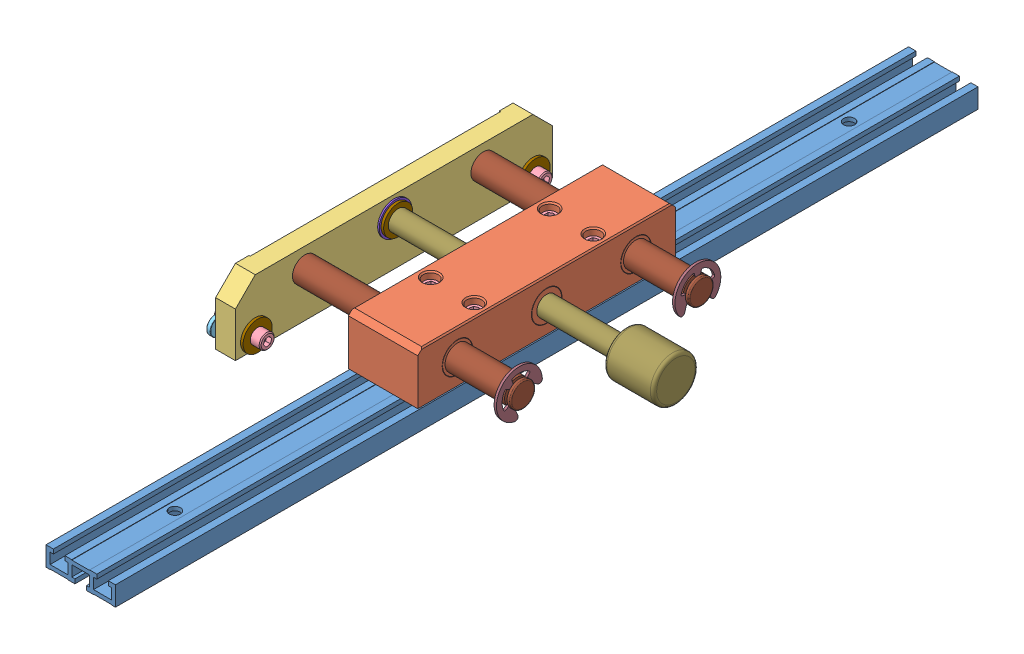
SolidWorks assembly MICRO ADJUST ASSEMBLY, configuration Default. Lengths in mm.
Overall size (204.2 53.63 552.45).
28 component instances, 13 part files, 65 mates.
Components (placement in the parent):
- MICRO ADJUST TWO-SLOT TRACK-1: MICRO ADJUST TWO-SLOT TRACK [Default] at origin
- MAIN BLOCK-1: MAIN BLOCK [Default] at (0 39.5605 0) x (0 0 1) z (-1 0 0)
- FENCE MOUNTING PLATE-1: FENCE MOUNTING PLATE [Default] at (-81.8748 35.687 0) x (0 0 -1) z (1 0 0)
- socket head cap screw_ai-1: socket head cap screw_ai [HX-SHCS 0.25-20x1.25x1.25-N] at (-13.97 35.5917 38.1) x (0 -1 0) z (-0.940414 0 -0.340032)
- socket head cap screw_ai-2: socket head cap screw_ai [HX-SHCS 0.25-20x1.25x1.25-N] at (-13.97 35.5917 -38.1) x (0 -1 0) z (0.999843 0 0.017747)
- socket head cap screw_ai-3: socket head cap screw_ai [HX-SHCS 0.25-20x1.25x1.25-N] at (13.97 35.5917 -38.1) x (0 -1 0) z (-0.291146 0 -0.956679)
- socket head cap screw_ai-4: socket head cap screw_ai [HX-SHCS 0.25-20x1.25x1.25-N] at (13.97 35.5917 38.1) x (0 -1 0) z (0.607644 0 -0.79421)
- OVAL NUT-.25 inch-1: OVAL NUT-.25 inch [Default] at (13.97 0.889 38.1) x (0 0 -1) z (1 0 0)
- OVAL NUT-.25 inch-2: OVAL NUT-.25 inch [Default] at (-13.97 0.889 38.1) x (0 0 1) z (-1 0 0)
- OVAL NUT-.25 inch-3: OVAL NUT-.25 inch [Default] at (-13.97 0.889 -38.1) x (0 0 1) z (-1 0 0)
- OVAL NUT-.25 inch-4: OVAL NUT-.25 inch [Default] at (13.97 0.889 -38.1) x (0 0 1) z (-1 0 0)
- socket button head cap screw_ai-1: socket button head cap screw_ai [SBHCSCREW 0.25-20x1.25-HX-N] at (-87.1326 22.8917 0) x (1 0 0) z (0 0.795965 0.605342)
- flat washer type a narrow_ai-1: flat washer type a narrow_ai [Preferred Narrow FW 0.25] at (-82.1288 22.8917 0) x (1 0 0) z (0 0.998178 -0.060343)
- wave spring lock washer_din-1: wave spring lock washer_din [DIN 137-B10-FSt] at (-75.5248 22.8917 0)
- flat washer type a wide_ai-1: flat washer type a wide_ai [Preferred Wide FW 0.25] at (-72.8738 22.8917 0) x (1 0 0) z (0 -0.237757 0.971325)
- socket head cap screw_ai-6: socket head cap screw_ai [HX-SHCS 0.25-20x1x1-N] at (-67.5238 2.6162 89.0016) x (-1 0 0) z (0 0.985182 0.171513)
- socket head cap screw_ai-7: socket head cap screw_ai [HX-SHCS 0.25-20x1x1-N] at (-67.5238 2.6162 -89.0016) x (-1 0 0) z (0 0.96667 0.256026)
- flat washer type a wide_ai-2: flat washer type a wide_ai [Preferred Wide FW 0.25] at (-73.8738 2.6162 -89.0016)
- flat washer type a wide_ai-3: flat washer type a wide_ai [Preferred Wide FW 0.25] at (-73.8738 2.6162 89.0016) x (1 0 0) z (0 0.473681 0.880696)
- socket countersunk head cap screw_ai-1: socket countersunk head cap screw_ai [SCHCSCREW 0.3125-24x1.25x1.25-HX-N] at (-87.6527 22.8917 57.15) x (1 0 0) z (0 0.88803 -0.459786)
- socket countersunk head cap screw_ai-3: socket countersunk head cap screw_ai [SCHCSCREW 0.3125-24x1.25x1.25-HX-N] at (-87.6527 22.8917 -57.15) x (1 0 0) z (0 -0.707697 0.706516)
- MICRO ADJUST SLIDING SHAFT-1: MICRO ADJUST SLIDING SHAFT [Default] at (-5.6748 22.8917 57.15) x (-1 0 0) z (0 0.234902 -0.972019)
- MICRO ADJUST SLIDING SHAFT-2: MICRO ADJUST SLIDING SHAFT [Default] at (-5.6748 22.8917 -57.15) x (-1 0 0) z (0 -0.354144 -0.935191)
- MICRO ADJUST THREADED SHAFT-1: MICRO ADJUST THREADED SHAFT [Default] at (0.1512 22.8917 0) x (-1 0 0) z (0 -0.993634 0.112654)
- OVAL NUT-.25 inch-5: OVAL NUT-.25 inch [Default] at (-91.3998 2.6162 -89.0016) x (0 0 1) z (0 -1 0)
- OVAL NUT-.25 inch-6: OVAL NUT-.25 inch [Default] at (-91.3998 2.6162 89.0016) x (0 0 1) z (0 -1 0)
- lock washer for shafts_din-1: lock washer for shafts_din [Lock washer DIN 6799 - 15] at (61.8892 22.8917 -57.15) x (0 0 -1) z (1 0 0)
- lock washer for shafts_din-2: lock washer for shafts_din [Lock washer DIN 6799 - 15] at (61.8892 22.8917 57.15) x (0 0.650404 -0.759589) z (1 0 0)
Mates (geometry in assembly coordinates):
- Coincident1: coincident aligned: plane of MICRO ADJUST TWO-SLOT TRACK_2-1 through (0 0 0) normal (0 0 1)
- Coincident2: coincident aligned: plane of MICRO ADJUST TWO-SLOT TRACK_2-1 through (0 0 0) normal (0 1 0)
- Coincident3: coincident aligned: plane of MICRO ADJUST TWO-SLOT TRACK_2-1 through (0 0 0) normal (1 0 0)
- Coincident4: coincident anti-aligned: plane of MICRO ADJUST TWO-SLOT TRACK_2-1 through (10.3116 6.223 276.225) normal (0 1 0); plane of MAIN BLOCK-1 through (0 6.223 0) normal (0 -1 0)
- Width1: width anti-aligned: plane of MAIN BLOCK-1 through (22.225 6.223 -82.55) normal (1 0 0); plane of MICRO ADJUST TWO-SLOT TRACK_2-1 through (-22.225 6.223 -82.55) normal (-1 0 0); plane of MAIN BLOCK-1 through (-22.225 6.223 276.225) normal (-1 0 0); plane of MICRO ADJUST TWO-SLOT TRACK_2-1 through (22.225 -6.223 276.225) normal (1 0 0)
- Width2: width anti-aligned: plane of MICRO ADJUST TWO-SLOT TRACK_2-1 through (0 0 276.225) normal (0 0 1); plane of MAIN BLOCK-1 through (0 0 -276.225) normal (0 0 -1); plane of MICRO ADJUST TWO-SLOT TRACK_2-1 through (22.225 6.223 -82.55) normal (0 0 -1); plane of MAIN BLOCK-1 through (22.225 6.223 82.55) normal (0 0 1)
- Concentric1: concentric anti-aligned: cylinder of MAIN BLOCK-1 through (-22.225 22.8917 0) axis (1 0 0) radius 6.35; cylinder of FENCE MOUNTING PLATE-1 through (-75.5248 22.8917 0) axis (-1 0 0) radius 3.3731
- Concentric2: concentric aligned: cylinder of MAIN BLOCK-1 through (-22.225 22.8917 57.15) axis (1 0 0) radius 7.9375; cylinder of FENCE MOUNTING PLATE-1 through (-104.0998 22.8917 57.15) axis (1 0 0) radius 4.0164
- Concentric3: concentric aligned: cylinder of MAIN BLOCK-1 through (-13.97 29.2417 38.1) axis (0 1 0) radius 4.7625; cylinder of socket head cap screw_ai-1 through (-13.97 67.3418 38.1) axis (0 1 0) radius 4.7625
- Concentric4: concentric aligned: cylinder of MAIN BLOCK-1 through (-13.97 29.2417 38.1) axis (0 1 0) radius 4.7625; cylinder of socket head cap screw_ai-1 through (-13.97 67.3418 38.1) axis (0 1 0) radius 3.175
- Concentric5: concentric aligned: cylinder of MAIN BLOCK-1 through (13.97 29.2417 38.1) axis (0 1 0) radius 4.7625; cylinder of socket head cap screw_ai-4 through (13.97 67.3418 38.1) axis (0 1 0) radius 3.175
- Concentric6: concentric aligned: cylinder of MAIN BLOCK-1 through (-13.97 29.2417 -38.1) axis (0 1 0) radius 4.7625; cylinder of socket head cap screw_ai-2 through (-13.97 67.3418 -38.1) axis (0 1 0) radius 3.175
- Concentric7: concentric aligned: cylinder of MAIN BLOCK-1 through (13.97 29.2417 -38.1) axis (0 1 0) radius 4.7625; cylinder of socket head cap screw_ai-3 through (13.97 67.3418 -38.1) axis (0 1 0) radius 3.175
- Coincident5: coincident anti-aligned: plane of MAIN BLOCK-1 through (-13.97 29.2417 38.1) normal (0 1 0); plane of socket head cap screw_ai-1 through (-15.5894 29.2417 42.5787) normal (0 -1 0)
- Coincident6: coincident anti-aligned: plane of MAIN BLOCK-1 through (13.97 29.2417 38.1) normal (0 1 0); plane of socket head cap screw_ai-4 through (10.1876 29.2417 35.2061) normal (0 -1 0)
- Coincident7: coincident anti-aligned: plane of MAIN BLOCK-1 through (-13.97 29.2417 -38.1) normal (0 1 0); plane of socket head cap screw_ai-2 through (-13.8855 29.2417 -42.8617) normal (0 -1 0)
- Coincident8: coincident anti-aligned: plane of MAIN BLOCK-1 through (13.97 29.2417 -38.1) normal (0 1 0); plane of socket head cap screw_ai-3 through (9.4138 29.2417 -36.7134) normal (0 -1 0)
- Parallel1: parallel aligned: plane of MICRO ADJUST TWO-SLOT TRACK_2-1 through (22.225 -6.223 276.225) normal (1 0 0); plane of OVAL NUT-.25 inch-1 through (19.558 3.429 45.212) normal (1 0 0)
- Concentric8: concentric aligned: cylinder of socket head cap screw_ai-4 through (13.97 67.3418 38.1) axis (0 1 0) radius 3.175; cylinder of OVAL NUT-.25 inch-1 through (13.97 -6.2952 38.1) axis (0 1 0) radius 2.54
- Coincident10: coincident anti-aligned: plane of MICRO ADJUST TWO-SLOT TRACK_2-1 through (8.2161 3.429 276.225) normal (0 -1 0); plane of OVAL NUT-.25 inch-1 through (13.97 3.429 45.212) normal (0 1 0)
- Parallel2: parallel anti-aligned: plane of MICRO ADJUST TWO-SLOT TRACK_2-1 through (22.225 -6.223 276.225) normal (1 0 0); plane of OVAL NUT-.25 inch-2 through (-19.558 3.429 30.988) normal (-1 0 0)
- Coincident12: coincident anti-aligned: plane of MICRO ADJUST TWO-SLOT TRACK_2-1 through (-19.5969 3.429 276.225) normal (0 -1 0); plane of OVAL NUT-.25 inch-2 through (-13.97 3.429 30.988) normal (0 1 0)
- Concentric9: concentric aligned: cylinder of socket head cap screw_ai-1 through (-13.97 67.3418 38.1) axis (0 1 0) radius 3.175; cylinder of OVAL NUT-.25 inch-2 through (-13.97 -6.2952 38.1) axis (0 1 0) radius 2.54
- Parallel3: parallel anti-aligned: plane of MICRO ADJUST TWO-SLOT TRACK_2-1 through (-22.225 6.223 276.225) normal (-1 0 0); plane of OVAL NUT-.25 inch-4 through (19.558 3.429 -45.212) normal (1 0 0)
- Parallel4: parallel anti-aligned: plane of MICRO ADJUST TWO-SLOT TRACK_2-1 through (-22.225 6.223 276.225) normal (-1 0 0); plane of OVAL NUT-.25 inch-3 through (-8.382 3.429 -45.212) normal (1 0 0)
- Coincident15: coincident anti-aligned: plane of MICRO ADJUST TWO-SLOT TRACK_2-1 through (-10.1354 3.429 276.225) normal (0 -1 0); plane of OVAL NUT-.25 inch-3 through (-13.97 3.429 -45.212) normal (0 1 0)
- Concentric10: concentric aligned: cylinder of socket head cap screw_ai-2 through (-13.97 67.3418 -38.1) axis (0 1 0) radius 3.175; cylinder of OVAL NUT-.25 inch-3 through (-13.97 -6.2952 -38.1) axis (0 1 0) radius 2.54
- Coincident16: coincident anti-aligned: plane of MICRO ADJUST TWO-SLOT TRACK_2-1 through (17.6776 3.429 276.225) normal (0 -1 0); plane of OVAL NUT-.25 inch-4 through (13.97 3.429 -45.212) normal (0 1 0)
- Concentric11: concentric aligned: cylinder of socket head cap screw_ai-3 through (13.97 67.3418 -38.1) axis (0 1 0) radius 3.175; cylinder of OVAL NUT-.25 inch-4 through (13.97 -6.2952 -38.1) axis (0 1 0) radius 2.54
- Concentric12: concentric aligned: cylinder of FENCE MOUNTING PLATE-1 through (-75.5248 22.8917 0) axis (-1 0 0) radius 3.3731; cylinder of socket button head cap screw_ai-1 through (-87.1326 22.8917 0) axis (-1 0 0) radius 3.175
- Concentric13: concentric aligned: cylinder of FENCE MOUNTING PLATE-1 through (-75.5248 22.8917 0) axis (-1 0 0) radius 3.3731; cylinder of flat washer type a narrow_ai-1 through (-117.0538 22.8917 0) axis (-1 0 0) radius 3.5687
- Coincident18: coincident anti-aligned: plane of FENCE MOUNTING PLATE-1 through (-82.1288 22.8917 0) normal (-1 0 0); plane of flat washer type a narrow_ai-1 through (-82.1288 22.6764 -3.5622) normal (1 0 0)
- Coincident19: coincident anti-aligned: plane of socket button head cap screw_ai-1 through (-83.7798 24.8137 -2.5272) normal (1 0 0); plane of flat washer type a narrow_ai-1 through (-83.7798 22.4128 -7.923) normal (-1 0 0)
- Concentric14: concentric aligned: cylinder of socket button head cap screw_ai-1 through (-87.1326 22.8917 0) axis (-1 0 0) radius 3.175; cylinder of wave spring lock washer_din-1 through (-74.5248 22.8917 0) axis (-1 0 0) radius 5.25
- Coincident20: coincident anti-aligned: plane of FENCE MOUNTING PLATE-1 through (-75.5248 -6.477 101.6) normal (1 0 0); plane of wave spring lock washer_din-1 through (-75.5248 22.8917 0) normal (-1 0 0)
- Concentric15: concentric aligned: cylinder of socket button head cap screw_ai-1 through (-87.1326 22.8917 0) axis (-1 0 0) radius 3.175; cylinder of flat washer type a wide_ai-1 through (-107.7988 22.8917 0) axis (-1 0 0) radius 3.9624
- Coincident22: coincident anti-aligned: plane of wave spring lock washer_din-1 through (-74.5248 22.8917 0) normal (1 0 0); plane of flat washer type a wide_ai-1 through (-74.5248 31.9462 2.2163) normal (-1 0 0)
- Coincident23: coincident anti-aligned: plane of FENCE MOUNTING PLATE-1 through (-75.5248 -6.477 101.6) normal (1 0 0); plane of flat washer type a wide_ai-2 through (-75.5248 11.938 -89.0016) normal (-1 0 0)
- Coincident24: coincident anti-aligned: plane of FENCE MOUNTING PLATE-1 through (-75.5248 -6.477 101.6) normal (1 0 0); plane of flat washer type a wide_ai-3 through (-75.5248 10.8259 84.586) normal (-1 0 0)
- Concentric17: concentric aligned: cylinder of FENCE MOUNTING PLATE-1 through (-75.5248 2.6162 -89.0016) axis (-1 0 0) radius 3.429; cylinder of flat washer type a wide_ai-2 through (-108.7988 2.6162 -89.0016) axis (-1 0 0) radius 3.9624
- Coincident25: coincident anti-aligned: plane of socket head cap screw_ai-7 through (-73.8738 1.3969 -84.3978) normal (-1 0 0); plane of flat washer type a wide_ai-2 through (-73.8738 6.5786 -89.0016) normal (1 0 0)
- Concentric18: concentric anti-aligned: cylinder of FENCE MOUNTING PLATE-1 through (-75.5248 2.6162 -89.0016) axis (-1 0 0) radius 3.429; cylinder of socket head cap screw_ai-7 through (-35.7738 2.6162 -89.0016) axis (1 0 0) radius 4.7625
- Concentric20: concentric aligned: cylinder of FENCE MOUNTING PLATE-1 through (-75.5248 2.6162 89.0016) axis (-1 0 0) radius 3.429; cylinder of flat washer type a wide_ai-3 through (-108.7988 2.6162 89.0016) axis (-1 0 0) radius 3.9624
- Coincident26: coincident anti-aligned: plane of socket head cap screw_ai-6 through (-73.8738 1.7994 93.6935) normal (-1 0 0); plane of flat washer type a wide_ai-3 through (-73.8738 6.1059 87.1247) normal (1 0 0)
- Concentric21: concentric anti-aligned: circle of socket head cap screw_ai-6; cylinder of flat washer type a wide_ai-3 through (-108.7988 2.6162 89.0016) axis (-1 0 0) radius 9.3218
- Concentric22: concentric anti-aligned: cylinder of FENCE MOUNTING PLATE-1 through (-104.0998 22.8917 57.15) axis (1 0 0) radius 4.0164; cylinder of socket countersunk head cap screw_ai-1 through (-87.6527 22.8917 57.15) axis (-1 0 0) radius 3.9688
- Coincident27: coincident anti-aligned: cone of FENCE MOUNTING PLATE-1 through (-82.6114 22.8917 57.15) axis (1 0 0); circle of socket countersunk head cap screw_ai-1
- Coincident28: coincident anti-aligned: cone of FENCE MOUNTING PLATE-1 through (-82.6114 22.8917 -57.15) axis (1 0 0); circle of socket countersunk head cap screw_ai-3
- Coincident29: coincident anti-aligned: plane of FENCE MOUNTING PLATE-1 through (-75.5248 -6.477 101.6) normal (1 0 0); plane of MICRO ADJUST SLIDING SHAFT-1 through (-75.5248 22.8917 57.15) normal (-1 0 0)
- Coincident30: coincident aligned: plane of FENCE MOUNTING PLATE-1 through (-75.5248 -6.477 101.6) normal (1 0 0); circle of MICRO ADJUST SLIDING SHAFT-2
- Concentric24: concentric anti-aligned: cylinder of socket countersunk head cap screw_ai-3 through (-87.6527 22.8917 -57.15) axis (-1 0 0) radius 3.9688; cylinder of MICRO ADJUST SLIDING SHAFT-2 through (84.0006 22.8917 -57.15) axis (1 0 0) radius 7.9375
- Concentric25: concentric anti-aligned: cylinder of socket countersunk head cap screw_ai-1 through (-87.6527 22.8917 57.15) axis (-1 0 0) radius 3.9688; cylinder of MICRO ADJUST SLIDING SHAFT-1 through (84.0006 22.8917 57.15) axis (1 0 0) radius 7.9375
- Coincident31: coincident anti-aligned: plane of flat washer type a wide_ai-1 through (-72.8738 26.7405 0.9421) normal (1 0 0); plane of MICRO ADJUST THREADED SHAFT-1 through (-72.8738 22.8917 0) normal (-1 0 0)
- Concentric26: concentric aligned: cylinder of MAIN BLOCK-1 through (-22.225 22.8917 0) axis (1 0 0) radius 6.35; cylinder of MICRO ADJUST THREADED SHAFT-1 through (134.9835 22.8917 0) axis (1 0 0) radius 6.35
- Distance2: distance = 3.175 mm anti-aligned: plane of FENCE MOUNTING PLATE-1 through (-88.2248 -6.477 -80.1624) normal (-1 0 0); plane of OVAL NUT-.25 inch-5 through (-91.3998 2.6162 -96.1136) normal (1 0 0)
- Concentric27: concentric anti-aligned: cylinder of socket head cap screw_ai-7 through (-35.7738 2.6162 -89.0016) axis (1 0 0) radius 3.175; cylinder of OVAL NUT-.25 inch-5 through (-84.2156 2.6162 -89.0016) axis (-1 0 0) radius 2.54
- Parallel5: parallel aligned: plane of FENCE MOUNTING PLATE-1 through (-81.8748 35.687 0) normal (0 1 0); plane of OVAL NUT-.25 inch-5 through (-93.9398 8.2042 -96.1136) normal (0 1 0)
- Parallel6: parallel aligned: plane of FENCE MOUNTING PLATE-1 through (-81.8748 35.687 0) normal (0 1 0); plane of OVAL NUT-.25 inch-6 through (-93.9398 8.2042 81.8896) normal (0 1 0)
- Concentric28: concentric anti-aligned: cylinder of socket head cap screw_ai-6 through (-35.7738 2.6162 89.0016) axis (1 0 0) radius 3.175; cylinder of OVAL NUT-.25 inch-6 through (-84.2156 2.6162 89.0016) axis (-1 0 0) radius 2.54
- Distance3: distance = 3.175 mm anti-aligned: plane of FENCE MOUNTING PLATE-1 through (-88.2248 -6.477 101.6) normal (-1 0 0); plane of OVAL NUT-.25 inch-6 through (-91.3998 2.6162 81.8896) normal (1 0 0)
- Concentric29: concentric aligned: cylinder of MICRO ADJUST SLIDING SHAFT-2 through (84.0006 22.8917 -57.15) axis (1 0 0) radius 7.9375; cylinder of lock washer for shafts_din-1 through (60.3892 22.8917 -57.15) axis (1 0 0) radius 7.5
- Coincident35: coincident anti-aligned: plane of MICRO ADJUST SLIDING SHAFT-2 through (61.8892 30.3148 -59.961) normal (-1 0 0); plane of lock washer for shafts_din-1 through (61.8892 22.8917 -57.15) normal (1 0 0)
- Concentric30: concentric aligned: cylinder of MICRO ADJUST SLIDING SHAFT-1 through (84.0006 22.8917 57.15) axis (1 0 0) radius 7.9375; cylinder of lock washer for shafts_din-2 through (60.3892 22.8917 57.15) axis (1 0 0) radius 7.5
- Coincident36: coincident anti-aligned: plane of MICRO ADJUST SLIDING SHAFT-1 through (61.8892 30.6072 59.0145) normal (-1 0 0); plane of lock washer for shafts_din-2 through (61.8892 22.8917 57.15) normal (1 0 0)
- LimitDistance2: limit distance = 38.1642 mm anti-aligned: plane of MAIN BLOCK-1 through (22.225 6.223 -82.55) normal (1 0 0); plane of lock washer for shafts_din-2 through (60.3892 22.8917 57.15) normal (-1 0 0)
